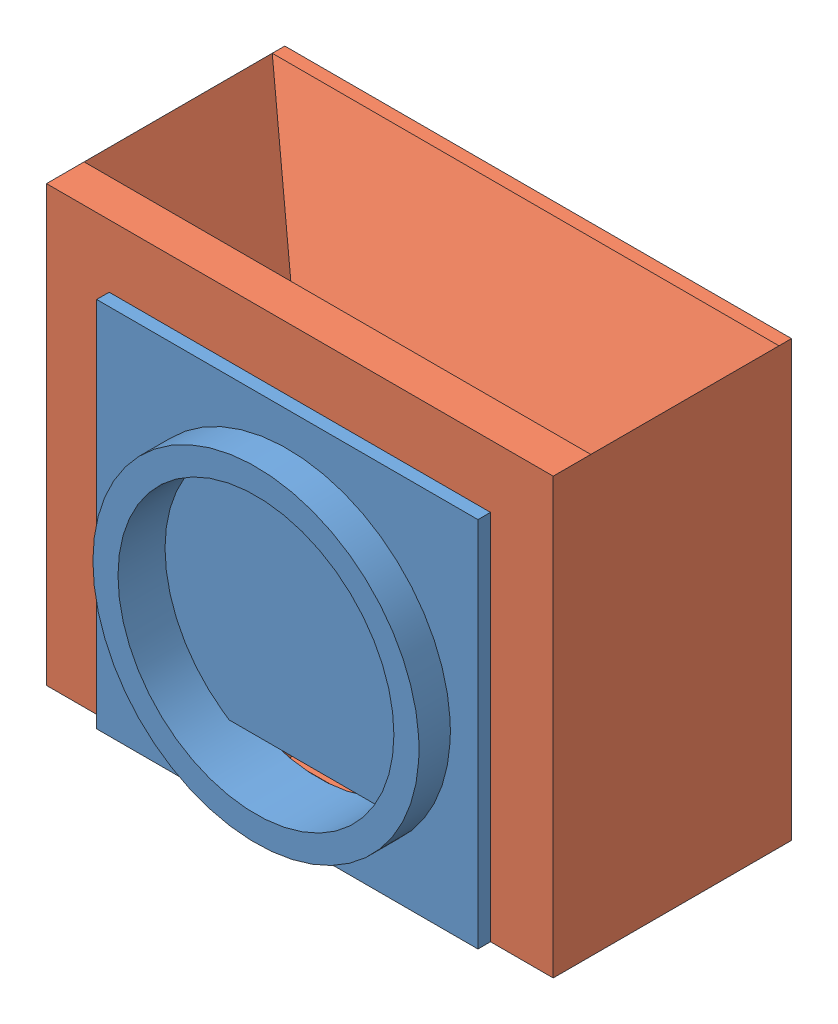
SolidWorks assembly funnelAssem, configuration Default. Lengths in mm.
Overall size (80.8 69.3 45).
2 component instances, 2 part files, 3 mates.
Components (placement in the parent):
- front plate-1: front plate [Default] at (-23.4089 33.7019 76.4853) size (60.8 59.3 10)
- funnel-1: funnel [Default] at (-23.4089 33.7019 71.4853) size (80.8 69.3 38)
Mates (geometry in assembly coordinates):
- Coincident5: coincident: plane of front plate-1 through (-53.8089 65.1019 71.4853) normal (0 1 0); plane of funnel-1 through (-53.8089 65.1019 68.4853) normal (0 -1 0)
- Coincident6: coincident: plane of front plate-1 through (-23.4089 33.7019 71.4853) normal (0 0 -1); plane of funnel-1 through (-23.4089 33.7019 71.4853) normal (0 0 1)
- Coincident7: coincident: plane of front plate-1 through (-53.8089 65.1019 71.4853) normal (-1 0 0); plane of funnel-1 through (-53.8089 7.3019 68.4853) normal (1 0 0)
